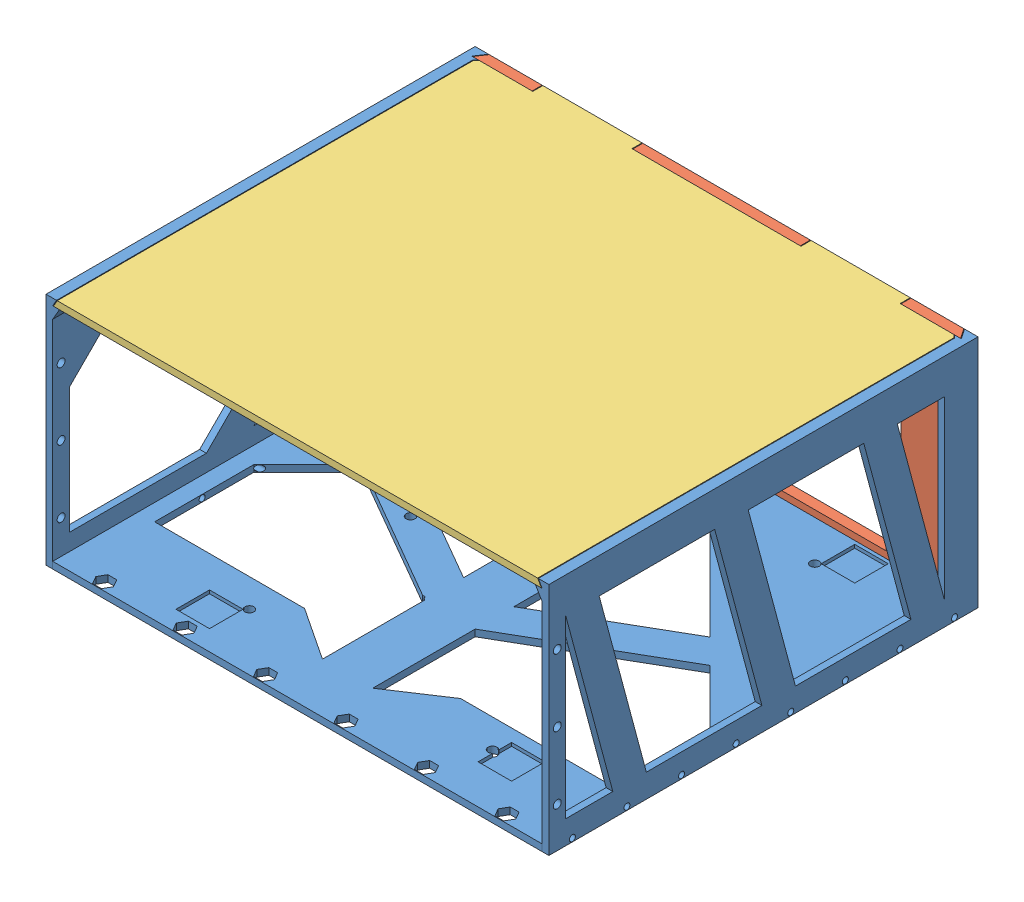
SolidWorks assembly Starfighter Assembly, configuration Default. Lengths in mm.
Overall size (185.42 88.9 162.56).
5 component instances, 5 part files, 13 mates.
Components (placement in the parent):
- backbone-1: backbone [Default] at origin size (234.95 96.52 6.35) (hidden)
- enclosure-shell-1: enclosure-shell [Default] at (15.875 0 0) size (190.5 88.9 162.56)
- back plate-1: back plate [Default] at (111.125 0 -156.21) size (184.91 86.36 3.81)
- top plate-1: top plate [Default] at (111.125 83.82 -152.4) size (184.91 2.54 162.56)
- Faceplates-1: Faceplates [Default] at (111.125 41.91 0) size (260.35 200.26 70.07) (hidden)
Mates (geometry in assembly coordinates):
- Coincident1: coordinate: point of backbone-1
- Coincident11: coincident aligned: plane of backbone-1 through (0 0 0) normal (0 0 1); plane of enclosure-shell-1 through (15.875 0 0) normal (0 0 1)
- Coincident12: coincident anti-aligned: plane of backbone-1 through (111.125 0 0) normal (1 0 0); plane of enclosure-shell-1 through (111.125 0 0) normal (-1 0 0)
- Coincident13: coincident aligned: plane of backbone-1 through (0 0 0) normal (0 1 0); plane of enclosure-shell-1 through (15.875 0 0) normal (0 1 0)
- Coincident14: coincident aligned: plane of enclosure-shell-1 through (111.125 0 0) normal (-1 0 0); plane of back plate-1 through (111.125 0 -156.21) normal (-1 0 0)
- Coincident15: coincident aligned: plane of enclosure-shell-1 through (15.875 83.82 0) normal (0 1 0); plane of back plate-1 through (111.125 83.82 -156.21) normal (0 1 0)
- Coincident16: coincident aligned: plane of enclosure-shell-1 through (15.875 0 -156.21) normal (0 0 -1); plane of back plate-1 through (111.125 0 -156.21) normal (0 0 -1)
- Coincident17: coincident anti-aligned: plane of enclosure-shell-1 through (15.875 83.82 0) normal (0 1 0); plane of top plate-1 through (111.125 83.82 -152.4) normal (0 -1 0)
- Coincident18: coincident aligned: plane of enclosure-shell-1 through (111.125 0 0) normal (-1 0 0); plane of top plate-1
- Coincident19: coincident aligned: plane of back plate-1 through (111.125 0 -152.4) normal (0 0 1); plane of top plate-1 through (111.125 83.82 -152.4) normal (0 0 1)
- Coincident20: coincident aligned: plane of enclosure-shell-1 through (111.125 0 0) normal (-1 0 0); plane of Faceplates-1 through (111.125 41.91 0) normal (-1 0 0)
- Coincident21: coincident aligned: plane of enclosure-shell-1 through (15.875 0 0) normal (0 1 0); plane of Faceplates-1 through (111.125 0 0) normal (0 1 0)
- Coincident22: coincident aligned: plane of enclosure-shell-1 through (15.875 0 0) normal (0 0 1); plane of Faceplates-1 through (111.125 41.91 0) normal (0 0 1)
